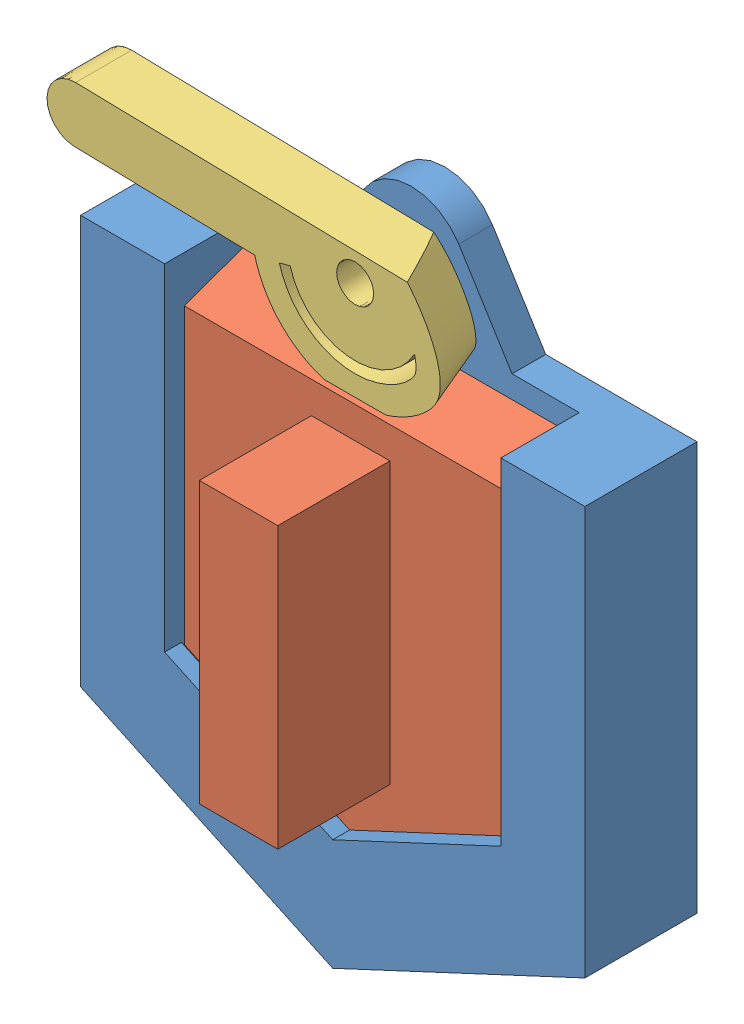
SolidWorks assembly #motagem, configuration Valor predeterminado. Lengths in mm.
Overall size (50.19 56.93 18.4).
3 component instances, 3 part files, 5 mates.
Components (placement in the parent):
- base-1: base [Valor predeterminado] at (-2.436 3.9976 60) size (45 56.93 10)
- ferramenta-1: ferramenta [Valor predeterminado] at (-2.436 9.716 63) size (29.65 41.12 15.4)
- alavanca-1: alavanca [Valor predeterminado] at (-2.436 33.9976 63) x (-0.999768 0.021534 0) z (0 0 1) size (35.22 11.76 5)
Mates (geometry in assembly coordinates):
- Largura1: width anti-aligned: plane of ferramenta-1 through (-17.261 27.216 68.4) normal (-1 0 0); plane of ferramenta-1 through (12.389 27.216 68.4) normal (1 0 0); plane of base-1 through (-17.436 -1.0024 63) normal (1 0 0); plane of base-1 through (12.564 -1.0024 63) normal (-1 0 0)
- Coincidente1: coincident anti-aligned: plane of base-1 through (-2.436 3.9976 63) normal (0 0 1); plane of ferramenta-1 through (-2.436 9.716 63) normal (0 0 -1)
- DistânciaLimite2: limit distance = 35 mm: line of ferramenta-1 through (12.389 26.9976 63) axis (-1 0 0); line of base-1 through (-2.436 -8.0024 68.5) axis (0 0 1)
- Concêntrico2: concentric aligned: cylinder of base-1 through (-2.436 33.9976 63) axis (0 0 -1) radius 1.65; cylinder of alavanca-1 through (-2.436 33.9976 68) axis (0 0 -1) radius 1.65
- Coincidente3: coincident anti-aligned: plane of base-1 through (-2.436 3.9976 63) normal (0 0 1); plane of alavanca-1 through (-27.4302 34.536 63) normal (0 0 -1)
